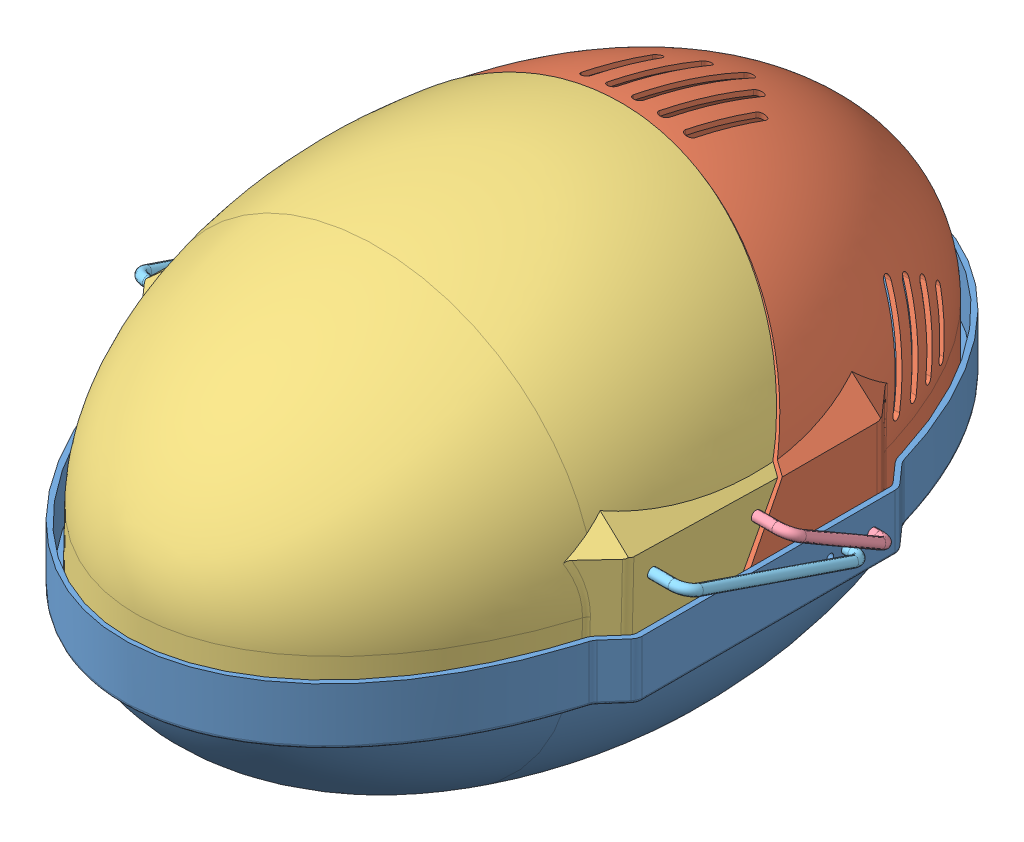
SolidWorks assembly Capsula, configuration Predeterminado. Lengths in mm.
Overall size (1079.29 607.16 1342.92).
7 component instances, 5 part files, 14 mates.
Components (placement in the parent):
- Base_fija-1: Base_fija [Predeterminado] at (-30.3348 76.8432 1.4467) size (463.37 329.5 797.31)
- Tapa_fija-1: Tapa_fija [Predeterminado] at (-30.3348 80.5932 1.4467) size (373.79 216.87 414.65)
- Tapa_movil-1: Tapa_movil [Predeterminado] at (-30.3348 82.3564 0.5156) x (1 0 0) z (0 0.023419 0.999726) size (382.54 306.89 468.26)
- correderachica-1: correderachica [Predeterminado] at (152.4238 102.3509 0.0472) x (0 -0.501054 -0.865416) z (-1 0 0) size (98.32 7.5 33.75)
- corredera grande-1: corredera grande [Predeterminado] at (152.4238 56.8432 -58.5533) x (0 0.323522 0.946221) z (-1 0 0) size (153.95 7.5 33.75)
- correderachica-2: correderachica [Predeterminado] at (-213.0934 56.8432 -78.5533) x (0 0.501054 0.865416) z (1 0 0) size (98.32 7.5 33.75)
- corredera grande-2: corredera grande [Predeterminado] at (-213.0934 56.8432 -58.5533) x (0 0.323522 0.946221) z (1 0 0) size (153.95 7.5 33.75)
Mates (geometry in assembly coordinates):
- Coincidente1: coincident aligned: plane of Base_fija-1 through (-30.3348 76.8432 1.4467) normal (1 0 0); plane of tapachica-1 through (-30.3348 80.5932 1.4467) normal (1 0 0)
- Coincidente3: coincident aligned: plane of Base_fija-1 through (-30.3348 76.8432 1.4467) normal (0 0 1); plane of tapachica-1 through (-30.3348 80.5932 1.4467) normal (0 0 1)
- Coincidente4: coincident anti-aligned: plane of Base_fija-1 through (-30.3348 36.8432 1.4467) normal (0 1 0); plane of tapachica-1 through (-30.3348 36.8432 1.4467) normal (0 -1 0)
- Coincidente5: coincident aligned: plane of Base_fija-1 through (-30.3348 76.8432 1.4467) normal (1 0 0); plane of Tapa_movil-1 through (-30.3348 82.2541 0.5555) normal (1 0 0)
- Concéntrica1: concentric aligned: circle of base2-1; circle of correderachica-1
- Concéntrica2: concentric aligned: circle of tapagrande-1; circle of correderachica-1
- Coincidente12: coincident aligned: circle of tapagrande-1; plane of correderachica-1 through (152.4238 102.249 0.1061) normal (-1 0 0)
- Concéntrica3: concentric anti-aligned: circle of base2-1; circle of corredera grande-1
- Coincidente14: coincident anti-aligned: circle of tapagrande-1; circle of corredera grande-1
- Concéntrica4: concentric aligned: circle of base2-1; circle of correderachica-2
- Concéntrica5: concentric anti-aligned: circle of tapagrande-1; circle of correderachica-2
- Coincidente18: coincident anti-aligned: circle of tapagrande-1; circle of corredera grande-2
- Concéntrica6: concentric aligned: circle of base2-1; circle of corredera grande-2
- Coincidente19: coincident anti-aligned: circle of Tapa_movil-1; circle of correderachica-2
